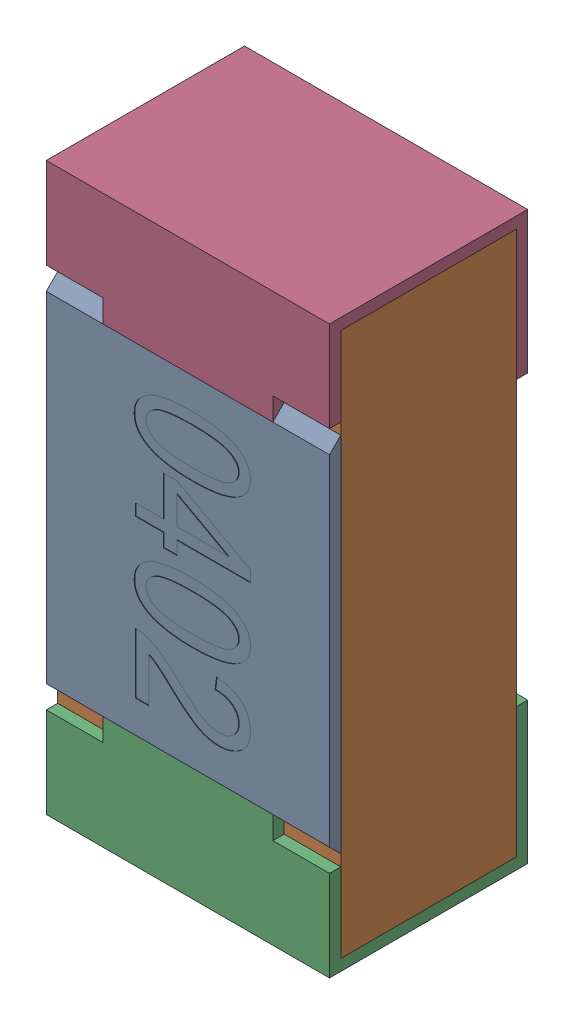
SolidWorks assembly R25, configuration Standard. Lengths in mm.
Overall size (0.5 1 0.35).
5 component instances, 4 part files, 0 mates.
Components (placement in the parent):
- R25-subassembly-1-1: R25-subassembly-1 [Standard] at (-14.4 -3.5001 0) x (0 -1 0) z (0 0 1) size (1 0.5 0.35)
  - User Library-R_0402-1: User Library-R_0402 [Standard] at origin size (0.64 0.5 0.02)
  - User Library-R_0402-1-1: User Library-R_0402-1 [Standard] at origin size (0.96 0.5 0.31)
  - User Library-R_0402-2-1: User Library-R_0402-2 [Standard] at origin size (0.25 0.5 0.35)
  - User Library-R_0402-3-1: User Library-R_0402-3 [Standard] at origin size (0.25 0.5 0.35)
